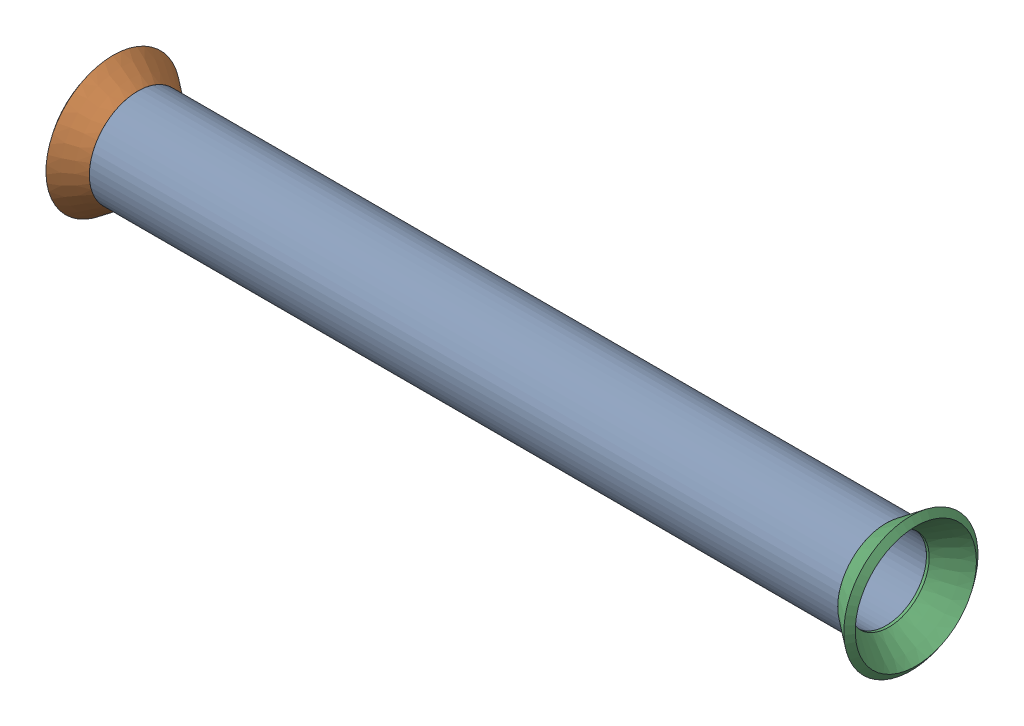
SolidWorks assembly Pipe 41, configuration Default. Lengths in mm.
Overall size (105.87 22.98 22.98).
3 component instances, 2 part files, 2 mates.
Components (placement in the parent):
- Copy of Part1-1: Copy of Part1 [Default<As Machined>] at (-669.012 708.4645 -133.3327) x (1 0 0) z (0 -0.924225 -0.381849) size (98.1 12.7 12.7)
- Flared pipe end - .5 inch-3: Flared pipe end - .5 inch [Default<As Machined>] at (-643.8092 453.1219 484.6961) x (0 -0.924225 0.381849) z (-1 0 0) size (17.59 17.59 3.89)
- Flared pipe end - .5 inch-4: Flared pipe end - .5 inch [Default<As Machined>] at (-545.7103 453.1219 484.6961) x (0 0.924225 -0.381849) z (1 0 0) size (17.59 17.59 3.89)
Mates (geometry in assembly coordinates):
- Coincident1699: coincident: circle of Copy of Part1-1; circle of Flared pipe end - .5 inch-3
- Coincident1701: coincident: circle of Copy of Part1-1; circle of Flared pipe end - .5 inch-4
